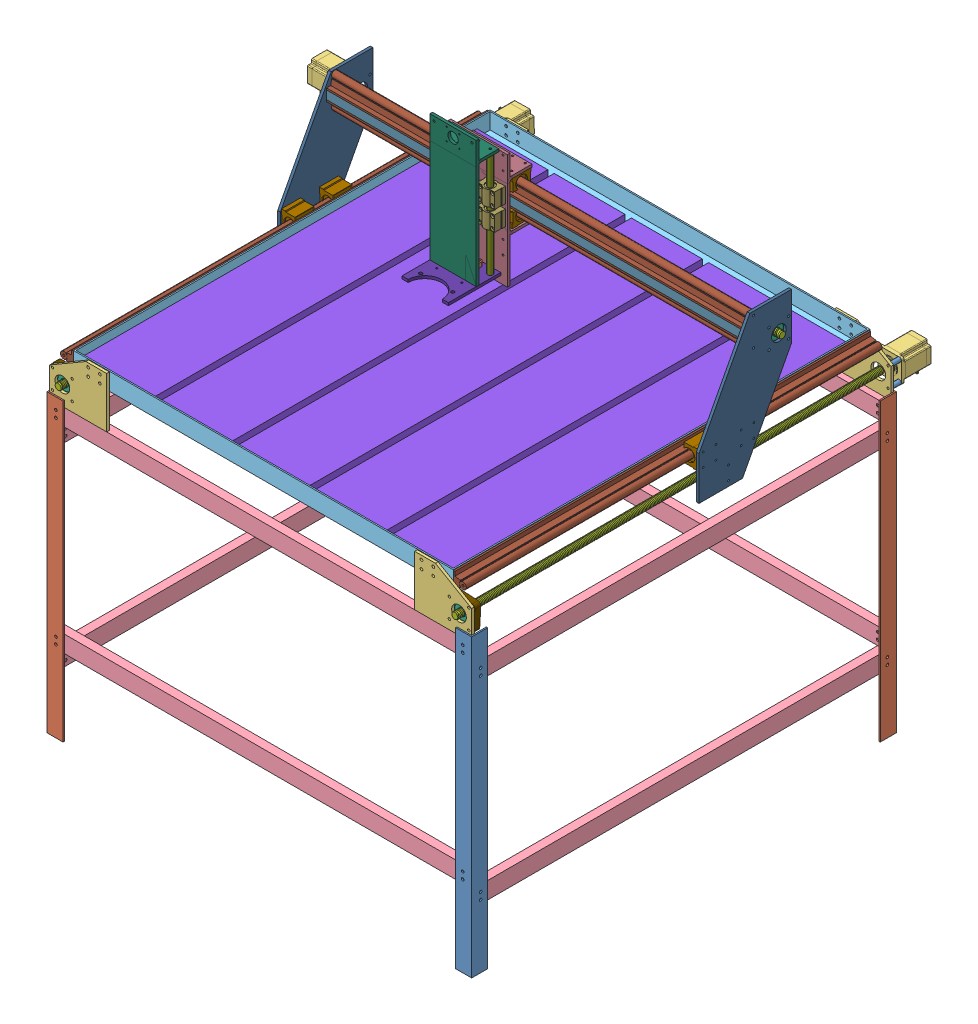
SolidWorks assembly Router_CNC_12x_21y_21z, configuration Predeterminado. Lengths in mm.
Overall size (1096.74 1103.61 1100).
67 component instances, 21 part files, 165 mates.
Components (placement in the parent):
- Perfil_L_3x38x700-2: Perfil_L_3x38x700 [Predeterminado] at (-108.3478 -597.6961 703.3947) size (38.1 700 38.1)
- Simetría_Perfil_L_3x38x700-8: Simetría_Perfil_L_3x38x700 [Predeterminado] at (821.8522 -597.6961 703.3947) x (-1 0 0) z (0 0 -1) size (38.1 700 38.1)
- Simetría_Perfil_L_3x38x700-9: Simetría_Perfil_L_3x38x700 [Predeterminado] at (-108.3478 -597.6961 1709.7947) size (38.1 700 38.1)
- Perfil_L_3x38x700-7: Perfil_L_3x38x700 [Predeterminado] at (821.8522 -597.6961 1709.7947) x (-1 0 0) z (0 0 -1) size (38.1 700 38.1)
- Planchuela_eje_X-1: Planchuela_eje_X [Predeterminado] at (-8.2478 87.3039 706.5947) size (135 120 6.35)
- caño_2x40x20x1000-1: caño_2x40x20x1000 [Predeterminado] at (-143.2478 47.3039 706.5947) x (0 0 1) z (0 1 0) size (20 1000 40)
- caño_2x40x20x1000-2: caño_2x40x20x1000 [Predeterminado] at (856.7522 47.3039 1706.5947) x (0 0 -1) z (0 1 0) size (20 1000 40)
- Planchuela_eje_X-4: Planchuela_eje_X [Predeterminado] at (721.7522 87.3039 712.9447) x (-1 0 0) z (0 0 -1) size (135 120 6.35)
- Planchuela_eje_X-5: Planchuela_eje_X [Predeterminado] at (-8.2478 87.3039 1700.2447) size (135 120 6.35)
- Planchuela_eje_X-6: Planchuela_eje_X [Predeterminado] at (721.7522 87.3039 1706.5947) x (-1 0 0) z (0 0 -1) size (135 120 6.35)
- caño_2x40x20x1000-3: caño_2x40x20x1000 [Predeterminado] at (-143.2478 -417.6961 706.5947) x (0 0 1) z (0 1 0) size (20 1000 40)
- caño_2x40x20x1000-4: caño_2x40x20x1000 [Predeterminado] at (-143.2478 -417.6961 1686.5947) x (0 0 1) z (0 1 0) size (20 1000 40)
- estructura_mesa_900x1000-2: estructura_mesa_900x1000 [Predeterminado] at (-93.2478 167.6539 1700.2447) x (0 0 1) z (0 1 0) size (987.3 900 41.2)
- Ruleman16-1: Ruleman16 [Predeterminado] at (-113.2478 132.3039 1689.1947) x (0.999999 0.001652 0) z (0 0 1) size (34.92 34.92 11.11)
- Ruleman16-2: Ruleman16 [Predeterminado] at (826.7522 132.3039 1689.1947) x (0.999994 -0.003589 0) z (0 0 1) size (34.92 34.92 11.11)
- rosca_acme_16-1: rosca_acme_16 [Predeterminado] at (826.7522 132.3039 706.5947) x (0.800397 0.59947 0) z (0 0 1) size (16.36 18.35 1011.38)
- rosca_acme_16-2: rosca_acme_16 [Predeterminado] at (-113.2478 132.3039 706.5947) x (-0.561284 -0.827623 0) z (0 0 1) size (16.36 18.35 1011.38)
- planchas_de_madera-1: planchas_de_madera [Predeterminado] at (809.8522 188.7539 747.1447) x (1 0 0) z (0 -1 0) size (900 950 18)
- SBR16UU Single Linear Bearing-1: SBR16UU Single Linear Bearing [Default] at (829.7086 187.6539 1142.042) x (0 -1 0) z (1 0 0) size (45 45.1 32.4)
- SBR16UU Single Linear Bearing-2: SBR16UU Single Linear Bearing [Default] at (829.7086 187.6539 1052.142) x (0 -1 0) z (1 0 0) size (45 45.1 32.4)
- SBR16UU Single Linear Bearing-3: SBR16UU Single Linear Bearing [Default] at (-116.2042 187.6539 1052.142) x (0 1 0) z (-1 0 0) size (45 45.1 32.4)
- SBR16UU Single Linear Bearing-4: SBR16UU Single Linear Bearing [Default] at (-116.2042 187.6539 1142.042) x (0 1 0) z (-1 0 0) size (45 45.1 32.4)
- Planchuela_eje_Y-1: Planchuela_eje_Y [Predeterminado] at (-136.1042 122.6539 1167.092) x (0 0 1) z (-1 0 0) size (219.4 330 6.35)
- Planchuela_eje_Y-2: Planchuela_eje_Y [Predeterminado] at (855.9586 122.6539 1167.092) x (0 0 1) z (-1 0 0) size (219.4 330 6.35)
- rosca_acme_16-3: rosca_acme_16 [Predeterminado] at (-145.7095 357.7964 977.6912) x (0 0.99074 -0.135769) z (1 0 0) size (16.36 18.35 1011.38)
- varilla16_con_soporte_de_aluminio-1: varilla16_con_soporte_de_aluminio [Predeterminado] at (-136.1042 407.5628 1030.4148) x (0 0 -1) z (0 -1 0) size (40 985 30.96)
- varilla16_con_soporte_de_aluminio-2: varilla16_con_soporte_de_aluminio [Predeterminado] at (-136.1042 374.1173 1044.9677) x (0 0 1) z (0 1 0) size (40 985 30.96)
- SBR16UU Single Linear Bearing-6: SBR16UU Single Linear Bearing [Default] at (193.7806 423.7964 1037.6912) x (0 0 -1) z (0 1 0) size (45 45.1 32.4)
- SBR16UU Single Linear Bearing-7: SBR16UU Single Linear Bearing [Default] at (283.6806 423.7964 1037.6912) x (0 0 -1) z (0 1 0) size (45 45.1 32.4)
- SBR16UU Single Linear Bearing-8: SBR16UU Single Linear Bearing [Default] at (193.7806 357.8836 1037.6912) x (0 0 1) z (0 -1 0) size (45 45.1 32.4)
- SBR16UU Single Linear Bearing-9: SBR16UU Single Linear Bearing [Default] at (283.6806 357.8836 1037.6912) x (0 0 1) z (0 -1 0) size (45 45.1 32.4)
- SCS12UU-1: SCS12UU [Valor predeterminado] at (283.4806 395.6964 1089.25) x (-1 0 0) z (0 1 0) size (42 29 36)
- SCS12UU-2: SCS12UU [Valor predeterminado] at (193.9806 348.6964 1089.25) x (-1 0 0) z (0 1 0) size (42 29 36)
- SCS12UU-3: SCS12UU [Valor predeterminado] at (283.4806 348.6964 1089.25) x (-1 0 0) z (0 1 0) size (42 29 36)
- varilla16_con_soporte_de_aluminio-4: varilla16_con_soporte_de_aluminio [Predeterminado] at (-99.9705 194.9304 715.2447) x (0 1 0) z (1 0 0) size (40 985 30.96)
- caño_2x40x20x1000-5: caño_2x40x20x1000 [Predeterminado] at (836.7522 0.3039 1706.5947) x (1 0 0) z (0 1 0) size (20 1000 40)
- caño_2x40x20x1000-6: caño_2x40x20x1000 [Predeterminado] at (-143.2478 0.3039 1706.5947) x (1 0 0) z (0 1 0) size (20 1000 40)
- caño_2x40x20x1000-7: caño_2x40x20x1000 [Predeterminado] at (836.7522 -459.6961 1706.5947) x (1 0 0) z (0 1 0) size (20 1000 40)
- caño_2x40x20x1000-8: caño_2x40x20x1000 [Predeterminado] at (-143.2478 -459.6961 1706.5947) x (1 0 0) z (0 1 0) size (20 1000 40)
- varilla16_con_soporte_de_aluminio-5: varilla16_con_soporte_de_aluminio [Predeterminado] at (813.475 180.3775 715.2447) x (0 -1 0) z (-1 0 0) size (40 985 30.96)
- planchuela_plegada_en_C_eje_Z-1: planchuela_plegada_en_C_eje_Z [Predeterminado] at (168.7306 226.6964 1074.25) x (-1 0 0) z (0 0 -1) size (140 272 113.51)
- caño_2x40x20x985-1: caño_2x40x20x985 [Predeterminado] at (-136.1042 400.84 1017.6912) x (0 -1 0) z (0 0 1) size (20 985.51 40)
- SCS12UU-5: SCS12UU [Valor predeterminado] at (193.9806 395.6964 1089.25) x (-1 0 0) z (0 1 0) size (42 29 36)
- planchuela_plegada_parte_de_arriba_Z-1: planchuela_plegada_parte_de_arriba_Z [Predeterminado] at (183.7306 249.5607 1132.7587) x (-1 0 0) z (0 0 -1) size (110 300 53.51)
- varilla_12-1: varilla_12 [Predeterminado] at (193.9806 249.5607 1089.25) x (1 0 0) z (0 1 0) size (12 12 250)
- varilla_12-2: varilla_12 [Predeterminado] at (283.4806 249.5607 1089.25) x (1 0 0) z (0 1 0) size (12 12 250)
- planchuela_parte_de_abajo_Z-1: planchuela_parte_de_abajo_Z [Predeterminado] at (293.7306 249.5607 1074.6489) x (1 0 0) z (0 -1 0) size (110 124 6.35)
- apoya_ruleman_int16mm_ext35mm-1: apoya_ruleman_int16mm_ext35mm [Predeterminado] at (818.696 10.4193 1686.1947) x (-0.058116 -0.99831 0) z (0 0 1) size (60 60 14.05)
- apoya_ruleman_int16mm_ext35mm-2: apoya_ruleman_int16mm_ext35mm [Predeterminado] at (-114.2069 10.1571 1686.1947) x (0 -1 0) z (0 0 1) size (60 60 14.05)
- Ruleman16-3: Ruleman16 [Predeterminado] at (838.5586 357.7964 977.6912) x (0 0 -1) z (1 0 0) size (34.92 34.92 11.11)
- apoya_ruleman_int16mm_ext35mm-3: apoya_ruleman_int16mm_ext35mm [Predeterminado] at (835.5586 356.8373 855.5444) x (0 0 -1) z (1 0 0) size (60 60 14.05)
- Separador_motores_20mm-1: Separador_motores_20mm [Predeterminado] at (-142.4542 334.6514 954.5462) x (0 0.679402 0.733766) z (-1 0 0) size (10.2 10.2 20)
- Separador_motores_20mm-2: Separador_motores_20mm [Predeterminado] at (-142.4542 334.6514 1000.8362) x (0 0.760834 0.648947) z (-1 0 0) size (10.2 10.2 20)
- Separador_motores_20mm-3: Separador_motores_20mm [Predeterminado] at (-142.4542 380.9414 954.5462) x (0 0.924225 0.381849) z (-1 0 0) size (10.2 10.2 20)
- Separador_motores_20mm-4: Separador_motores_20mm [Predeterminado] at (-142.4542 380.9414 1000.8362) x (0 0.948656 0.316311) z (-1 0 0) size (10.2 10.2 20)
- Separador_motores_20mm-5: Separador_motores_20mm [Predeterminado] at (-90.1028 109.1539 706.5947) x (-0.923728 -0.383049 0) z (0 0 -1) size (10.2 10.2 20)
- Separador_motores_20mm-6: Separador_motores_20mm [Predeterminado] at (803.6072 155.4539 706.5947) x (-0.923728 -0.383049 0) z (0 0 -1) size (10.2 10.2 20)
- Separador_motores_20mm-7: Separador_motores_20mm [Predeterminado] at (-90.1028 155.4539 686.5947) size (10.2 10.2 20)
- Separador_motores_20mm-8: Separador_motores_20mm [Predeterminado] at (-136.3928 155.4539 686.366) size (10.2 10.2 20)
- Separador_motores_20mm-9: Separador_motores_20mm [Predeterminado] at (803.6072 109.1539 706.6902) x (-0.923728 -0.383049 0) z (0 0 -1) size (10.2 10.2 20)
- Separador_motores_20mm-10: Separador_motores_20mm [Predeterminado] at (849.8972 155.4539 706.5947) x (-0.97104 -0.238916 0) z (0 0 -1) size (10.2 10.2 20)
- apoya_ruleman_int8mm_ext22mm-1: apoya_ruleman_int8mm_ext22mm [Predeterminado] at (201.3523 249.5607 1086.1756) x (-1 0 0) z (0 1 0) size (41 41 10)
- Separador_motores_20mm-11: Separador_motores_20mm [Predeterminado] at (-136.3928 109.1539 686.5947) size (10.2 10.2 20)
- Separador_motores_20mm-12: Separador_motores_20mm [Predeterminado] at (849.8972 109.1539 686.5947) x (0.923095 0.384573 0) z (0 0 1) size (10.2 10.2 20)
- NEMA 23.step-1: NEMA 23.step [Predeterminado] at (-232.4542 358.2214 978.1162) x (0 -1 0) z (0 0 1) size (76.2 95 56.2)
- NEMA 23.step-2: NEMA 23.step [Predeterminado] at (827.1772 131.8839 616.5947) x (0 -1 0) z (-1 0 0) size (76.2 95 56.2)
- NEMA 23.step-3: NEMA 23.step [Predeterminado] at (-113.1429 133.0398 616.5947) x (-0.999909 -0.013491 0) z (-0.013491 0.999909 0) size (76.2 95 56.2)
Mates (geometry in assembly coordinates):
- Coincidente40: coincident anti-aligned: plane of Simetría_Perfil_L_3x38x700-9 through (-108.3478 -597.6961 1706.5947) normal (0 0 -1); plane of caño_2x40x20x1000-2 through (856.7522 47.3039 1706.5947) normal (0 0 1)
- Coincidente41: coincident anti-aligned: circle of L 30x30x700-7; circle of caño rectangular 30x20x1200-2
- Coincidente42: coincident aligned: circle of SimetríaL 30x30x700-9; circle of caño rectangular 30x20x1200-2
- Coincidente43: coincident anti-aligned: cylinder of Simetría_Perfil_L_3x38x700-9 through (-125.2478 59.3039 1716.5947) axis (0 0 -1) radius 3.175; circle of caño rectangular 30x20x1200-2
- Coincidente44: coincident anti-aligned: circle of L 30x30x700-7; cylinder of caño_2x40x20x1000-2 through (838.7522 59.3039 706.5947) axis (0 0 1) radius 3.175
- Coincidente47: coincident anti-aligned: plane of Simetría_Perfil_L_3x38x700-8 through (821.8522 -597.6961 706.5947) normal (0 0 1); plane of caño_2x40x20x1000-1 through (-143.2478 47.3039 706.5947) normal (0 0 -1)
- Coincidente50: coincident aligned: circle of SimetríaL 30x30x700-8; circle of caño rectangular 30x20x1200-1
- Coincidente51: coincident aligned: circle of SimetríaL 30x30x700-8; cylinder of caño_2x40x20x1000-1 through (838.7522 59.3039 1706.5947) axis (0 0 -1) radius 3.175
- Coincidente53: coincident: point of Planchuela_eje_X-1; point of caño_2x40x20x1000-1
- Coincidente59: coincident: point of Planchuela_eje_X-1; line of caño_2x40x20x1000-1 through (856.7522 87.3039 706.5947) axis (-1 0 0)
- Coincidente60: coincident: point of caño_2x40x20x1000-2; point of Planchuela_eje_X-5
- Coincidente61: coincident: plane of caño_2x40x20x1000-2 through (856.7522 87.3039 1686.5947) normal (0 1 0); point of Planchuela_eje_X-5
- Coincidente62: coincident: point of caño_2x40x20x1000-2; point of Planchuela_eje_X-6
- Coincidente63: coincident: plane of caño_2x40x20x1000-2 through (856.7522 87.3039 1686.5947) normal (0 1 0); point of Planchuela_eje_X-6
- Coincidente65: coincident aligned: circle of SimetríaL 30x30x700-8; circle of caño rectangular 30x20x1200-3
- Coincidente66: coincident anti-aligned: circle of L 30x30x700-2; cylinder of caño_2x40x20x1000-3 through (-125.2478 -389.6961 1706.5947) axis (0 0 -1) radius 3.175
- Coincidente67: coincident aligned: circle of SimetríaL 30x30x700-9; circle of caño rectangular 30x20x1200-4
- Concéntrica24: concentric aligned: cylinder of Perfil_L_3x38x700-7 through (838.7522 -389.6961 1716.5947) axis (0 0 -1) radius 3.175; cylinder of caño_2x40x20x1000-4 through (838.7522 -389.6961 2686.5947) axis (0 0 -1) radius 3.175
- Paralelo1: parallel: line of caño_2x40x20x1000-2 through (-143.2478 87.3039 1706.5947) axis (1 0 0); plane of Planchuela_eje_X-5 through (-8.2478 87.3039 1700.2447) normal (0 0 -1)
- Coincidente69: coincident anti-aligned: plane of L 30x30x700-2 through (-108.3478 -597.6961 706.5947) normal (0 0 1); plane of Planchuela_eje_X-1 through (-8.2478 87.3039 706.5947) normal (0 0 -1)
- Coincidente70: coincident anti-aligned: plane of Simetría_Perfil_L_3x38x700-9 through (-108.3478 -597.6961 1706.5947) normal (0 0 -1); plane of Planchuela_eje_X-5 through (-8.2478 87.3039 1706.5947) normal (0 0 1)
- Coincidente71: coincident: plane of caño_2x40x20x1000-2 through (856.7522 87.3039 1686.5947) normal (0 1 0); point of Planchuela_eje_X-6
- Coincidente72: coincident: plane of caño_2x40x20x1000-2 through (856.7522 87.3039 1686.5947) normal (0 1 0); point of Planchuela_eje_X-6
- Coincidente73: coincident anti-aligned: plane of Perfil_L_3x38x700-7 through (821.8522 -597.6961 1706.5947) normal (0 0 -1); plane of Planchuela_eje_X-6 through (721.7522 87.3039 1706.5947) normal (0 0 1)
- Concéntrica34: concentric anti-aligned: cylinder of Planchuela_eje_X-5 through (-113.2478 132.3039 1693.8947) axis (0 0 1) radius 17.4625; cylinder of Ruleman16-1 through (-113.2478 132.3039 1700.3067) axis (0 0 -1) radius 17.4625
- Concéntrica35: concentric aligned: cylinder of Planchuela_eje_X-6 through (826.7522 132.3039 1712.9447) axis (0 0 -1) radius 17.4625; cylinder of Ruleman16-2 through (826.7522 132.3039 1700.3067) axis (0 0 -1) radius 17.4625
- Tangente1: tangent: cylinder of Ruleman16-1 through (-113.2478 132.3039 1700.3067) axis (0 0 -1) radius 7.9375; curve of rosca acme-2
- Coincidente89: coincident aligned: plane of Planchuela_eje_X-1 through (-8.2478 87.3039 706.5947) normal (0 0 -1); plane of rosca_acme_16-2 through (-113.2478 132.3039 706.5947) normal (0 0 -1)
- Tangente3: tangent: cylinder of Ruleman16-2 through (826.7522 132.3039 1700.3067) axis (0 0 -1) radius 7.9375; curve of rosca acme-1
- Coincidente90: coincident aligned: plane of Planchuela_eje_X-4 through (721.7522 87.3039 706.5947) normal (0 0 -1); plane of rosca_acme_16-1 through (826.7522 132.3039 706.5947) normal (0 0 -1)
- Coincidente91: coincident anti-aligned: plane of estructura_mesa_900x1000-2 through (803.6522 208.8539 1697.1447) normal (0 0 -1); plane of planchas_de_madera-1 through (809.8522 170.7539 1697.1447) normal (0 0 1)
- Coincidente93: coincident anti-aligned: plane of Planchuela_eje_X-4 through (721.7522 87.3039 712.9447) normal (0 0 1); plane of estructura_mesa_900x1000-2 through (-93.2478 170.7539 712.9447) normal (0 0 -1)
- Paralelo2: parallel anti-aligned: cylinder of Planchuela_eje_X-4 through (765.7522 197.7789 706.5947) axis (0 0 1) radius 3.175; cylinder of estructura_mesa_900x1000-2 through (765.7522 197.7789 1712.9447) axis (0 0 -1) radius 3.175
- Coincidente96: coincident anti-aligned: plane of estructura_mesa_900x1000-2 through (-93.2478 170.7539 1700.2447) normal (0 1 0); plane of planchas_de_madera-1 through (809.8522 170.7539 747.1447) normal (0 -1 0)
- Paralelo4: parallel aligned: plane of Planchuela_eje_X-4 through (856.7522 87.3039 706.5947) normal (1 0 0); plane of SBR16UU Single Linear Bearing-2 through (848.6086 187.6539 1029.592) normal (1 0 0)
- Paralelo5: parallel aligned: plane of Planchuela_eje_X-6 through (856.7522 87.3039 1700.2447) normal (1 0 0); plane of SBR16UU Single Linear Bearing-1 through (848.6086 187.6539 1119.492) normal (1 0 0)
- Paralelo6: parallel aligned: plane of Planchuela_eje_X-5 through (-143.2478 87.3039 1706.5947) normal (-1 0 0); plane of SBR16UU Single Linear Bearing-4 through (-135.1042 187.6539 1119.492) normal (-1 0 0)
- Paralelo7: parallel aligned: plane of SBR16UU Single Linear Bearing-3 through (-135.1042 187.6539 1029.592) normal (-1 0 0); plane of Planchuela_eje_X-1 through (-143.2478 87.3039 712.9447) normal (-1 0 0)
- Coincidente103: coincident aligned: plane of SBR16UU Single Linear Bearing-1 through (829.7086 187.6539 1119.492) normal (0 0 -1); plane of SBR16UU Single Linear Bearing-4 through (-116.2042 187.6539 1119.492) normal (0 0 -1)
- Coincidente104: coincident aligned: plane of SBR16UU Single Linear Bearing-2 through (829.7086 187.6539 1029.592) normal (0 0 -1); plane of SBR16UU Single Linear Bearing-3 through (-116.2042 187.6539 1029.592) normal (0 0 -1)
- Coincidente105: coincident aligned: circle of SBR16UU Single Linear Bearing-4; circle of Planchuela de eje y-1
- Coincidente106: coincident aligned: circle of SBR16UU Single Linear Bearing-3; circle of Planchuela de eje y-1
- Coincidente109: coincident anti-aligned: circle of SBR16UU Single Linear Bearing-2; circle of Planchuela de eje y-2
- Concéntrica46: concentric aligned: cylinder of SBR16UU Single Linear Bearing-1 through (849.6086 171.6039 1157.092) axis (1 0 0) radius 2.1; cylinder of Planchuela_eje_Y-2 through (849.6086 171.6039 1157.092) axis (1 0 0) radius 2.1
- Concéntrica47: concentric anti-aligned: cylinder of Planchuela_eje_Y-1 through (-129.7542 357.7964 977.6912) axis (-1 0 0) radius 17.4625; circle of rosca acme-3
- Coincidente110: coincident anti-aligned: plane of Simetría_Perfil_L_3x38x700-8 through (821.8522 -597.6961 706.5947) normal (0 0 1); plane of Planchuela_eje_X-4 through (721.7522 87.3039 706.5947) normal (0 0 -1)
- Coincidente111: coincident anti-aligned: plane of caño_2x40x20x1000-1 through (-143.2478 87.3039 726.5947) normal (0 1 0); plane of Planchuela_eje_X-4 through (721.7522 87.3039 706.5947) normal (0 -1 0)
- Coincidente112: coincident anti-aligned: plane of Simetría_Perfil_L_3x38x700-8 through (856.7522 102.3039 741.4947) normal (-1 0 0); plane of Planchuela_eje_X-4 through (856.7522 87.3039 706.5947) normal (1 0 0)
- Concéntrica49: concentric anti-aligned: cylinder of Planchuela_eje_X-6 through (765.7522 197.7789 1700.2447) axis (0 0 1) radius 3.175; circle of mesa 1000x1000-2
- Coincidente115: coincident anti-aligned: circle of Planchuela de agarre-1; cylinder of estructura_mesa_900x1000-2 through (-52.2478 197.7789 1712.9447) axis (0 0 -1) radius 3.175
- Coincidente116: coincident anti-aligned: plane of estructura_mesa_900x1000-2 through (-90.1478 208.8539 716.0447) normal (1 0 0); plane of planchas_de_madera-1 through (-90.1478 170.7539 747.1447) normal (-1 0 0)
- Paralelo9: parallel aligned: plane of varilla16_con_soporte_de_aluminio-1 through (848.8958 407.5628 1030.4148) normal (1 0 0); plane of varilla16_con_soporte_de_aluminio-2 through (848.8958 374.1173 1044.9677) normal (1 0 0)
- Concéntrica53: concentric anti-aligned: cylinder of varilla16_con_soporte_de_aluminio-1 through (848.8958 423.7964 1037.6912) axis (-1 0 0) radius 8; cylinder of SBR16UU Single Linear Bearing-6 through (175.2806 423.7964 1037.6912) axis (1 0 0) radius 8
- Concéntrica54: concentric anti-aligned: cylinder of varilla16_con_soporte_de_aluminio-1 through (848.8958 423.7964 1037.6912) axis (-1 0 0) radius 8; cylinder of SBR16UU Single Linear Bearing-7 through (265.1806 423.7964 1037.6912) axis (1 0 0) radius 8
- Concéntrica55: concentric anti-aligned: cylinder of varilla16_con_soporte_de_aluminio-2 through (848.8958 357.8836 1037.6912) axis (-1 0 0) radius 8; cylinder of SBR16UU Single Linear Bearing-8 through (175.2806 357.8836 1037.6912) axis (1 0 0) radius 8
- Concéntrica56: concentric anti-aligned: cylinder of varilla16_con_soporte_de_aluminio-2 through (848.8958 357.8836 1037.6912) axis (-1 0 0) radius 8; cylinder of SBR16UU Single Linear Bearing-9 through (265.1806 357.8836 1037.6912) axis (1 0 0) radius 8
- Paralelo14: parallel anti-aligned: plane of varilla16_con_soporte_de_aluminio-1 through (848.8958 404.94 1030.4148) normal (0 1 0); plane of SBR16UU Single Linear Bearing-7 through (264.6306 411.2964 1037.6912) normal (0 -1 0)
- Paralelo15: parallel anti-aligned: plane of varilla16_con_soporte_de_aluminio-1 through (848.8958 404.94 1030.4148) normal (0 1 0); plane of SBR16UU Single Linear Bearing-6 through (174.7306 411.2964 1037.6912) normal (0 -1 0)
- Coincidente154: coincident anti-aligned: line of SBR16UU Single Linear Bearing-7 through (306.2306 411.7964 1058.6662) axis (0 1 0); line of SBR16UU Single Linear Bearing-9 through (306.2306 369.8836 1058.6662) axis (0 -1 0)
- Coincidente155: coincident anti-aligned: line of SBR16UU Single Linear Bearing-6 through (216.3306 411.7964 1058.6662) axis (0 1 0); line of SBR16UU Single Linear Bearing-8 through (216.3306 369.8836 1058.6662) axis (0 -1 0)
- Coincidente158: coincident anti-aligned: plane of estructura_mesa_900x1000-2 through (-93.2478 170.7539 1700.2447) normal (-1 0 0); plane of varilla16_con_soporte_de_aluminio-4 through (-93.2478 194.9304 1700.2447) normal (1 0 0)
- Coincidente159: coincident anti-aligned: line of estructura_mesa_900x1000-2 through (-93.2478 208.8539 1700.2447) axis (0 -1 0); line of varilla16_con_soporte_de_aluminio-4 through (-93.2478 167.6539 1700.2447) axis (0 1 0)
- Coincidente161: coincident anti-aligned: line of estructura_mesa_900x1000-2 through (-93.2478 167.6539 712.9447) axis (0 0 1); line of varilla16_con_soporte_de_aluminio-4 through (-93.2478 167.6539 1700.2447) axis (0 0 -1)
- Concéntrica57: concentric anti-aligned: cylinder of SBR16UU Single Linear Bearing-3 through (-116.2042 187.6539 1033.642) axis (0 0 1) radius 8; cylinder of varilla16_con_soporte_de_aluminio-4 through (-116.2042 187.6539 1700.2447) axis (0 0 -1) radius 8
- Concéntrica58: concentric anti-aligned: cylinder of SBR16UU Single Linear Bearing-4 through (-116.2042 187.6539 1123.542) axis (0 0 1) radius 8; cylinder of varilla16_con_soporte_de_aluminio-4 through (-116.2042 187.6539 1700.2447) axis (0 0 -1) radius 8
- Coincidente162: coincident aligned: cylinder of SBR16UU Single Linear Bearing-4 through (-136.1042 203.7039 1157.092) axis (-1 0 0) radius 2.1; circle of Planchuela_eje_Y-1
- Coincidente166: coincident aligned: circle of Simetría_Perfil_L_3x38x700-8; circle of caño_2x40x20x1000-5
- Concéntrica62: concentric anti-aligned: circle of Simetría_Perfil_L_3x38x700-8; circle of caño_2x40x20x1000-5
- Concéntrica63: concentric aligned: cylinder of Perfil_L_3x38x700-7 through (866.7522 28.3039 1688.5947) axis (-1 0 0) radius 3.175; cylinder of caño_2x40x20x1000-5 through (1836.7522 28.3039 1688.5947) axis (-1 0 0) radius 3.175
- Concéntrica64: concentric aligned: cylinder of Perfil_L_3x38x700-7 through (866.7522 12.3039 1688.5947) axis (-1 0 0) radius 3.175; cylinder of caño_2x40x20x1000-5 through (1836.7522 12.3039 1688.5947) axis (-1 0 0) radius 3.175
- Concéntrica65: concentric anti-aligned: cylinder of Perfil_L_3x38x700-2 through (-125.2478 75.3039 696.5947) axis (0 0 1) radius 3.175; circle of caño_2x40x20x1000-1
- Concéntrica66: concentric anti-aligned: circle of Perfil_L_3x38x700-2; cylinder of caño_2x40x20x1000-1 through (-125.2478 59.3039 1706.5947) axis (0 0 -1) radius 3.175
- Coincidente169: coincident anti-aligned: circle of Perfil_L_3x38x700-2; circle of caño_2x40x20x1000-8
- Concéntrica67: concentric anti-aligned: circle of Perfil_L_3x38x700-2; circle of caño_2x40x20x1000-8
- Concéntrica68: concentric aligned: circle of Simetría_Perfil_L_3x38x700-9; circle of caño_2x40x20x1000-8
- Concéntrica69: concentric anti-aligned: cylinder of Simetría_Perfil_L_3x38x700-9 through (-153.2478 -447.6961 1688.5947) axis (1 0 0) radius 3.175; cylinder of caño_2x40x20x1000-8 through (856.7522 -447.6961 1688.5947) axis (-1 0 0) radius 3.175
- Coincidente172: coincident aligned: circle of Simetría_Perfil_L_3x38x700-8; circle of caño_2x40x20x1000-7
- Coincidente173: coincident anti-aligned: circle of Simetría_Perfil_L_3x38x700-8; cylinder of caño_2x40x20x1000-7 through (1836.7522 -447.6961 724.5947) axis (-1 0 0) radius 3.175
- Concéntrica70: concentric anti-aligned: circle of Perfil_L_3x38x700-7; circle of caño_2x40x20x1000-7
- Coincidente176: coincident anti-aligned: circle of Perfil_L_3x38x700-2; circle of caño_2x40x20x1000-6
- Concéntrica72: concentric anti-aligned: circle of Perfil_L_3x38x700-2; circle of caño_2x40x20x1000-6
- Concéntrica73: concentric anti-aligned: cylinder of Simetría_Perfil_L_3x38x700-9 through (-153.2478 28.3039 1688.5947) axis (1 0 0) radius 3.175; cylinder of caño_2x40x20x1000-6 through (856.7522 28.3039 1688.5947) axis (-1 0 0) radius 3.175
- Coincidente178: coincident anti-aligned: plane of estructura_mesa_900x1000-2 through (806.7522 170.7539 1700.2447) normal (1 0 0); plane of varilla16_con_soporte_de_aluminio-5 through (806.7522 180.3775 1700.2447) normal (-1 0 0)
- Coincidente179: coincident aligned: line of estructura_mesa_900x1000-2 through (806.7522 208.8539 1700.2447) axis (0 -1 0); line of varilla16_con_soporte_de_aluminio-5 through (806.7522 207.6539 1700.2447) axis (0 -1 0)
- Coincidente180: coincident aligned: line of estructura_mesa_900x1000-2 through (806.7522 167.6539 1700.2447) axis (0 0 -1); line of varilla16_con_soporte_de_aluminio-5 through (806.7522 167.6539 1700.2447) axis (0 0 -1)
- Concéntrica74: concentric anti-aligned: cylinder of SBR16UU Single Linear Bearing-1 through (829.7086 187.6539 1123.542) axis (0 0 1) radius 8; cylinder of varilla16_con_soporte_de_aluminio-5 through (829.7086 187.6539 1700.2447) axis (0 0 -1) radius 8
- Concéntrica75: concentric anti-aligned: cylinder of SBR16UU Single Linear Bearing-2 through (829.7086 187.6539 1033.642) axis (0 0 1) radius 8; cylinder of varilla16_con_soporte_de_aluminio-5 through (829.7086 187.6539 1700.2447) axis (0 0 -1) radius 8
- Concéntrica88: concentric anti-aligned: circle of SBR16UU Single Linear Bearing-6; circle of planchuela_plegada_en_C_eje_Z-1
- Concéntrica89: concentric anti-aligned: circle of SBR16UU Single Linear Bearing-7; circle of planchuela_plegada_en_C_eje_Z-1
- Coincidente184: coincident anti-aligned: plane of SBR16UU Single Linear Bearing-7 through (261.1306 443.6964 1037.6912) normal (0 1 0); plane of planchuela_plegada_en_C_eje_Z-1 through (168.7306 443.6964 1287.7412) normal (0 -1 0)
- Coincidente187: coincident anti-aligned: plane of Planchuela_eje_Y-1 through (-136.1042 122.6539 1167.092) normal (1 0 0); plane of caño_2x40x20x985-1 through (-136.1042 380.84 1017.6912) normal (-1 0 0)
- Coincidente189: coincident aligned: plane of varilla16_con_soporte_de_aluminio-1 through (848.8958 407.5628 1017.6912) normal (0 0 -1); plane of caño_2x40x20x985-1 through (-136.1042 380.84 1017.6912) normal (0 0 -1)
- Coincidente190: coincident anti-aligned: plane of varilla16_con_soporte_de_aluminio-1 through (848.8958 400.84 1030.4148) normal (0 -1 0); plane of caño_2x40x20x985-1 through (-136.1042 400.84 1017.6912) normal (0 1 0)
- Coincidente193: coincident anti-aligned: plane of varilla16_con_soporte_de_aluminio-2 through (848.8958 380.84 1044.9677) normal (0 1 0); plane of caño_2x40x20x985-1 through (-136.1042 380.84 1017.6912) normal (0 -1 0)
- Coincidente194: coincident aligned: plane of varilla16_con_soporte_de_aluminio-2 through (848.8958 374.1173 1017.6912) normal (0 0 -1); plane of caño_2x40x20x985-1 through (-136.1042 380.84 1017.6912) normal (0 0 -1)
- Concéntrica97: concentric anti-aligned: circle of SCS12UU-3; circle of planchuela_plegada_en_C_eje_Z-1
- Coincidente197: coincident anti-aligned: circle of SCS12UU-3; cylinder of planchuela_plegada_en_C_eje_Z-1 through (268.2306 353.6964 1067.9) axis (0 0 -1) radius 2.25
- Concéntrica94: concentric anti-aligned: cylinder of SCS12UU-2 through (209.2306 379.6964 1099.25) axis (0 0 1) radius 2.25; cylinder of planchuela_plegada_en_C_eje_Z-1 through (209.2306 379.6964 1067.9) axis (0 0 -1) radius 2.25
- Concéntrica95: concentric anti-aligned: circle of SCS12UU-2; circle of planchuela_plegada_en_C_eje_Z-1
- Concéntrica96: concentric anti-aligned: cylinder of SCS12UU-2 through (178.7306 379.6964 1099.25) axis (0 0 1) radius 2.25; cylinder of planchuela_plegada_en_C_eje_Z-1 through (178.7306 379.6964 1067.9) axis (0 0 -1) radius 2.25
- Coincidente200: coincident anti-aligned: plane of SCS12UU-2 through (184.4806 384.6964 1074.25) normal (0 0 -1); plane of planchuela_plegada_en_C_eje_Z-1 through (168.7306 226.6964 1074.25) normal (0 0 1)
- Coincidente201: coincident anti-aligned: plane of SCS12UU-3 through (304.4806 384.6964 1074.25) normal (0 0 -1); plane of planchuela_plegada_en_C_eje_Z-1 through (168.7306 226.6964 1074.25) normal (0 0 1)
- Coincidente202: coincident anti-aligned: plane of SCS12UU-1 through (304.4806 431.6964 1074.25) normal (0 0 -1); plane of planchuela_plegada_en_C_eje_Z-1 through (168.7306 226.6964 1074.25) normal (0 0 1)
- Concéntrica98: concentric anti-aligned: circle of SCS12UU-1; circle of planchuela_plegada_en_C_eje_Z-1
- Concéntrica99: concentric anti-aligned: circle of SCS12UU-1; circle of planchuela_plegada_en_C_eje_Z-1
- Concéntrica100: concentric anti-aligned: cylinder of planchuela_plegada_en_C_eje_Z-1 through (209.2306 426.6964 1067.9) axis (0 0 -1) radius 2.25; cylinder of SCS12UU-5 through (209.2306 426.6964 1099.25) axis (0 0 1) radius 2.25
- Concéntrica101: concentric anti-aligned: cylinder of planchuela_plegada_en_C_eje_Z-1 through (178.7306 400.6964 1067.9) axis (0 0 -1) radius 2.25; cylinder of SCS12UU-5 through (178.7306 400.6964 1099.25) axis (0 0 1) radius 2.25
- Coincidente206: coincident anti-aligned: plane of planchuela_plegada_en_C_eje_Z-1 through (168.7306 226.6964 1074.25) normal (0 0 1); plane of SCS12UU-5 through (184.4806 431.6964 1074.25) normal (0 0 -1)
- Coincidente207: coincident anti-aligned: circle of planchuela_plegada_parte_de_arriba_Z-1; circle of varilla_12-1
- Coincidente208: coincident anti-aligned: circle of planchuela_plegada_parte_de_arriba_Z-1; circle of varilla_12-2
- Concéntrica102: concentric aligned: cylinder of SCS12UU-1 through (283.4806 431.6964 1089.25) axis (0 -1 0) radius 6; cylinder of varilla_12-2 through (283.4806 499.5607 1089.25) axis (0 -1 0) radius 6
- Concéntrica103: concentric aligned: cylinder of SCS12UU-5 through (193.9806 431.6964 1089.25) axis (0 -1 0) radius 6; cylinder of varilla_12-1 through (193.9806 499.5607 1089.25) axis (0 -1 0) radius 6
- Coincidente209: coincident aligned: circle of varilla_12-1; circle of planchuela_parte_de_abajo_Z-1
- Concéntrica104: concentric aligned: cylinder of varilla_12-2 through (283.4806 264.5607 1089.25) axis (0 -1 0) radius 2.5; circle of planchuela_parte_de_abajo_Z-1
- Coincidente210: coincident anti-aligned: line of varilla16_con_soporte_de_aluminio-2 through (-136.1042 380.84 1017.6912) axis (0 0 1); line of caño_2x40x20x985-1 through (-136.1042 380.84 1057.6912) axis (0 0 -1)
- Coincidente211: coincident aligned: line of varilla16_con_soporte_de_aluminio-1 through (-136.1042 400.84 1057.6912) axis (0 0 -1); line of caño_2x40x20x985-1 through (-136.1042 400.84 1057.6912) axis (0 0 -1)
- Concéntrica109: concentric aligned: circle of Planchuela_eje_Y-1; circle of varilla16_con_soporte_de_aluminio-1
- Paralelo16: parallel anti-aligned: line of Planchuela_eje_Y-1 through (-142.4542 432.7964 947.6912) axis (0 -1 0); line of caño_2x40x20x985-1 through (-136.1042 380.84 1057.6912) axis (0 1 0)
- Concéntrica111: concentric anti-aligned: circle of Ruleman16-2; circle of apoya_ruleman_int16mm_ext35mm-1
- Coincidente215: coincident anti-aligned: plane of Ruleman16-2 through (826.7522 132.3039 1689.1947) normal (0 0 -1); plane of apoya_ruleman_int16mm_ext35mm-1 through (826.7522 132.3039 1689.1947) normal (0 0 1)
- Coincidente216: coincident anti-aligned: plane of Planchuela_eje_X-6 through (721.7522 87.3039 1700.2447) normal (0 0 -1); plane of apoya_ruleman_int16mm_ext35mm-1 through (851.2032 154.0647 1700.2447) normal (0 0 1)
- Paralelo17: parallel aligned: cylinder of Planchuela_eje_X-6 through (803.6072 155.4539 1712.9447) axis (0 0 -1) radius 2.75; cylinder of apoya_ruleman_int16mm_ext35mm-1 through (851.2032 154.0647 1700.2447) axis (0 0 -1) radius 2.75
- Paralelo18: parallel aligned: cylinder of Planchuela_eje_X-6 through (849.8972 109.1539 1712.9447) axis (0 0 -1) radius 2.75; cylinder of apoya_ruleman_int16mm_ext35mm-1 through (802.3013 110.5432 1700.2447) axis (0 0 -1) radius 2.75
- Coincidente220: coincident anti-aligned: plane of Ruleman16-1 through (-113.2478 132.3039 1689.1947) normal (0 0 -1); plane of apoya_ruleman_int16mm_ext35mm-2 through (-113.2478 132.3039 1689.1947) normal (0 0 1)
- Concéntrica117: concentric anti-aligned: circle of Ruleman16-1; circle of apoya_ruleman_int16mm_ext35mm-2
- Coincidente221: coincident anti-aligned: plane of Planchuela_eje_X-5 through (-8.2478 87.3039 1700.2447) normal (0 0 -1); plane of apoya_ruleman_int16mm_ext35mm-2 through (-90.1028 155.4489 1700.2447) normal (0 0 1)
- Coincidente222: coincident aligned: plane of Planchuela_eje_X-5 through (-143.2478 87.3039 1706.5947) normal (-1 0 0); plane of apoya_ruleman_int16mm_ext35mm-2 through (-143.2478 109.1589 1700.2447) normal (-1 0 0)
- Coincidente223: coincident anti-aligned: plane of Ruleman16-3 through (838.5586 357.7964 977.6912) normal (-1 0 0); plane of apoya_ruleman_int16mm_ext35mm-3 through (838.5586 357.7964 977.6912) normal (1 0 0)
- Concéntrica118: concentric aligned: cylinder of Ruleman16-3 through (849.6706 357.7964 977.6912) axis (-1 0 0) radius 7.9375; cylinder of apoya_ruleman_int16mm_ext35mm-3 through (838.5586 357.7964 977.6912) axis (-1 0 0) radius 15
- Coincidente224: coincident anti-aligned: plane of Planchuela_eje_Y-2 through (849.6086 122.6539 1167.092) normal (-1 0 0); plane of apoya_ruleman_int16mm_ext35mm-3 through (849.6086 380.9414 1000.8362) normal (1 0 0)
- Concéntrica119: concentric aligned: cylinder of Planchuela_eje_Y-2 through (862.3086 380.9414 1000.8362) axis (-1 0 0) radius 2.75; cylinder of apoya_ruleman_int16mm_ext35mm-3 through (849.6086 380.9414 1000.8362) axis (-1 0 0) radius 2.75
- Concéntrica120: concentric aligned: cylinder of Planchuela_eje_Y-2 through (862.3086 334.6514 954.5462) axis (-1 0 0) radius 2.75; cylinder of apoya_ruleman_int16mm_ext35mm-3 through (849.6086 334.6514 954.5462) axis (-1 0 0) radius 2.75
- Concéntrica122: concentric aligned: circle of Planchuela_eje_Y-1; circle of Separador_motores_20mm-4
- Concéntrica123: concentric aligned: circle of Planchuela_eje_Y-1; circle of Separador_motores_20mm-2
- Coincidente225: coincident aligned: plane of Planchuela_eje_Y-1 through (-142.4542 122.6539 1167.092) normal (-1 0 0); circle of Separador_motores_20mm-2
- Concéntrica124: concentric aligned: circle of Planchuela_eje_Y-1; circle of Separador_motores_20mm-1
- Coincidente226: coincident anti-aligned: plane of Planchuela_eje_Y-1 through (-142.4542 122.6539 1167.092) normal (-1 0 0); plane of Separador_motores_20mm-1 through (-142.4542 334.6514 954.5462) normal (1 0 0)
- Concéntrica125: concentric aligned: circle of Planchuela_eje_Y-1; circle of Separador_motores_20mm-3
- Coincidente227: coincident anti-aligned: plane of Planchuela_eje_Y-1 through (-142.4542 122.6539 1167.092) normal (-1 0 0); plane of Separador_motores_20mm-3 through (-142.4542 380.9414 954.5462) normal (1 0 0)
- Concéntrica126: concentric anti-aligned: circle of Planchuela_eje_X-1; circle of Separador_motores_20mm-5
- Coincidente228: coincident anti-aligned: plane of Planchuela_eje_X-1 through (-8.2478 87.3039 706.5947) normal (0 0 -1); plane of Separador_motores_20mm-5 through (-90.1028 109.1539 706.5947) normal (0 0 1)
- Concéntrica127: concentric aligned: circle of Planchuela_eje_X-1; circle of Separador_motores_20mm-7
- Concéntrica128: concentric aligned: circle of Planchuela_eje_X-1; circle of Separador_motores_20mm-8
- Concéntrica129: concentric aligned: circle of Planchuela_eje_X-4; circle of Separador_motores_20mm-6
- Concéntrica130: concentric aligned: circle of Planchuela_eje_X-4; circle of Separador_motores_20mm-10
- Concéntrica131: concentric aligned: circle of Planchuela_eje_X-4; circle of Separador_motores_20mm-9
- Coincidente231: coincident anti-aligned: plane of planchuela_parte_de_abajo_Z-1 through (238.7306 249.5607 1199.6489) normal (0 1 0); plane of apoya_ruleman_int8mm_ext22mm-1 through (253.7306 249.5607 1116.25) normal (0 -1 0)
- Concéntrica132: concentric aligned: cylinder of planchuela_parte_de_abajo_Z-1 through (253.7306 253.2107 1116.25) axis (0 -1 0) radius 2.5; cylinder of apoya_ruleman_int8mm_ext22mm-1 through (253.7306 259.5607 1116.25) axis (0 -1 0) radius 2.5
- Concéntrica133: concentric aligned: cylinder of planchuela_parte_de_abajo_Z-1 through (223.7306 253.2107 1116.25) axis (0 -1 0) radius 2.5; cylinder of apoya_ruleman_int8mm_ext22mm-1 through (223.7306 259.5607 1116.25) axis (0 -1 0) radius 2.5
- Concéntrica134: concentric aligned: circle of Planchuela_eje_X-1; circle of Separador_motores_20mm-11
- Coincidente232: coincident anti-aligned: plane of Planchuela_eje_X-1 through (-8.2478 87.3039 706.5947) normal (0 0 -1); circle of Separador_motores_20mm-11
- Concéntrica135: concentric anti-aligned: circle of Planchuela_eje_X-4; circle of Separador_motores_20mm-12
- Coincidente233: coincident anti-aligned: plane of Planchuela_eje_X-4 through (721.7522 87.3039 706.5947) normal (0 0 -1); plane of Separador_motores_20mm-12 through (849.8972 109.1539 706.5947) normal (0 0 1)
- Concéntrica136: concentric anti-aligned: circle of Separador_motores_20mm-1; circle of NEMA 23.step-1
- Paralelo20: parallel anti-aligned: cylinder of Separador_motores_20mm-4 through (-162.4542 380.9414 1000.8362) axis (1 0 0) radius 2.6; cylinder of NEMA 23.step-1 through (-162.4542 381.7914 1001.6862) axis (-1 0 0) radius 2.375
- Paralelo21: parallel anti-aligned: cylinder of Separador_motores_20mm-3 through (-162.4542 380.9414 954.5462) axis (1 0 0) radius 2.6; cylinder of NEMA 23.step-1 through (-162.4542 381.7914 954.5462) axis (-1 0 0) radius 2.375
- Coincidente234: coincident anti-aligned: plane of Separador_motores_20mm-3 through (-162.4542 380.9414 954.5462) normal (-1 0 0); plane of NEMA 23.step-1 through (-162.4542 358.2214 978.1162) normal (1 0 0)
- Paralelo24: parallel aligned: plane of Planchuela_eje_Y-1 through (-142.4542 322.6539 947.6912) normal (0 0 -1); plane of NEMA 23.step-1 through (-162.4542 330.1214 950.0162) normal (0 0 -1)
- Coincidente236: coincident anti-aligned: plane of Planchuela_eje_Y-1 through (-142.4542 122.6539 1167.092) normal (-1 0 0); plane of Separador_motores_20mm-4 through (-142.4542 380.9414 1000.8362) normal (1 0 0)
- Concéntrica145: concentric aligned: circle of Separador_motores_20mm-11; circle of NEMA 23.step-3
- Coincidente241: coincident: circle of Separador_motores_20mm-7; moEndPointRef_w of NEMA 23.step-3
- Concéntrica146: concentric anti-aligned: circle of Separador_motores_20mm-6; circle of NEMA 23.step-2
- Coincidente245: coincident anti-aligned: plane of Separador_motores_20mm-10 through (849.8972 155.4539 686.5947) normal (0 0 -1); plane of NEMA 23.step-2 through (827.1772 131.8839 686.5947) normal (0 0 1)
- Coincidente247: coincident anti-aligned: plane of Planchuela_eje_X-4 through (721.7522 87.3039 706.5947) normal (0 0 -1); plane of Separador_motores_20mm-10 through (849.8972 155.4539 706.5947) normal (0 0 1)
- Paralelo26: parallel aligned: plane of Planchuela_eje_X-4 through (856.7522 87.3039 706.5947) normal (1 0 0); plane of NEMA 23.step-2 through (855.2772 103.7839 686.5947) normal (1 0 0)
